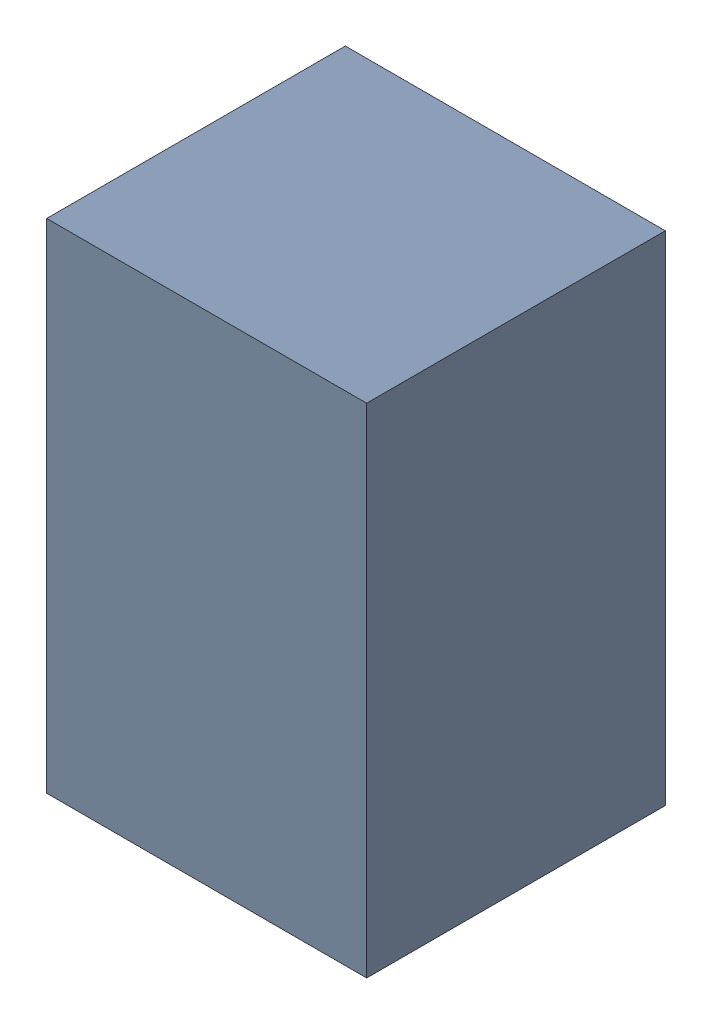
SolidWorks assembly CL, configuration Default. Lengths in mm.
Overall size (1.35 2.1 1.26).
2 component instances, 1 part files, 0 mates.
Components (placement in the parent):
- 407985696_1-1: 407985696_1 [Default] at (28.575 17.2596 0.0127) size (1.35 2.1 1.26)
  - Extruded_6-1: Extruded_6 [Default] at origin size (1.35 2.1 1.26)
